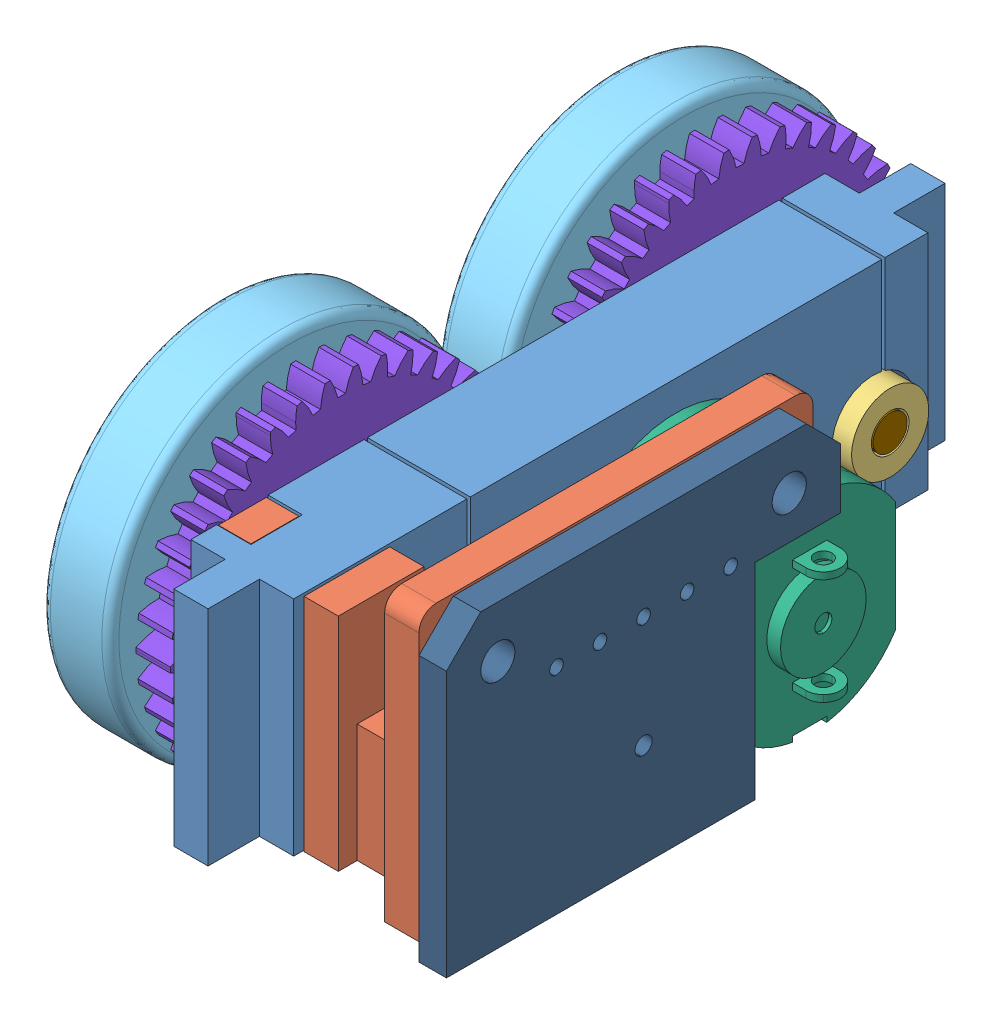
SolidWorks assembly CumBanh1, configuration Default. Lengths in mm.
Overall size (26.61 22.13 47.3).
19 component instances, 12 part files, 39 mates.
Components (placement in the parent):
- Cum Banh 1-1: Cum Banh 1 [Default] at (16.5178 20.2239 29.5226) x (0 0 -1) z (1 0 0) size (43 13 7.5)
- Ga encoder 1-1: Ga encoder 1 [Default] at (28.5178 23.2543 41.2226) x (0 0 -1) z (0 -1 0) size (23 14 16.6)
- Ga nam chamV3-1: Ga nam chamV3 [Default] at (21.0178 20.2239 18.0226) x (1 0 0) z (0 -0.059126 0.998251) size (2.5 4.5 4.5)
- Ga nam chamV3.1-1: Ga nam chamV3.1 [Default] at (20.5178 20.2239 41.0226) x (1 0 0) z (0 -0.620557 0.784161) size (7 7.5 7.5)
- Lop banh xe-1: Lop banh xe [Default] at (6.5178 20.2239 41.0226) size (4 21 21)
- N20 DC MOTOR Truc dai-1: N20 DC MOTOR Truc dai [Default] at (30.3178 20.1445 29.5225) x (0 1 0) z (0 0 1) size (12.48 22.6 10.65)
- Nam cham-1: Nam cham [Default] at (26.5178 20.2239 41.0226) x (0 -0.952578 -0.304296) z (1 0 0) size (4 4 2)
- Part4-1: Part4 [Default] at (12.5178 20.2239 41.0226) x (-1 0 0) z (0 0 -1) (suppressed, hidden)
- Spur gear 0.5M 38T-1: Spur gear 0.5M 38T [Default] at (12.5178 20.2239 41.0226) size (5 19.95 20)
- Truc 2x20-1: Truc 2x20 [Default] at (14.5178 20.2239 41.0226) x (0 0 -1) z (1 0 0) size (2 2 18)
- MT6701 Ver2-1: MT6701 Ver2 [Default] at (32.1278 20.2239 41.0226) x (0 0 -1) z (-1 0 0) size (23 17.5 3.61)
- Part4-2: Part4 [Default] at (12.5178 20.2239 18.0226) x (-1 0 0) z (0 0 -1) (suppressed, hidden)
- Truc 2x20-2: Truc 2x20 [Default] at (14.5178 20.2239 18.0226) x (0 0.989004 -0.147887) z (1 0 0) size (2 2 18)
- Lop banh xe-2: Lop banh xe [Default] at (6.5178 20.2239 18.0226) size (4 21 21)
- Spur gear 0.5M 38T-2: Spur gear 0.5M 38T [Default] at (12.5178 20.2239 18.0226) x (1 0 0) z (0 0.027407 0.999624) size (5 19.95 20)
- Vong bi 2x5x2.5-2: Vong bi 2x5x2.5 [Default] at (18.627 20.2239 41.0226) x (0 0 -1) z (1 0 0) size (5 5 3)
- Vong bi 2x5x2.5-3: Vong bi 2x5x2.5 [Default] at (21.627 20.2239 41.0226) x (0 0 -1) z (1 0 0) size (5 5 3)
- Vong bi 2x5x2.5-4: Vong bi 2x5x2.5 [Default] at (18.627 20.2239 18.0226) x (0 0 -1) z (1 0 0) size (5 5 3)
- Vong bi 2x5x2.5-6: Vong bi 2x5x2.5 [Default] at (21.627 20.2239 18.0226) x (0 0 -1) z (1 0 0) size (5 5 3)
Mates (geometry in assembly coordinates):
- Concentric1: concentric aligned: cylinder of Cum Banh 1-1 through (22.5178 20.2239 41.0226) axis (-1 0 0) radius 2.6; cylinder of Truc 2x20-1 through (23.5178 20.2239 41.0226) axis (-1 0 0) radius 1
- Concentric2: concentric aligned: cylinder of Cum Banh 1-1 through (22.5178 20.2239 41.0226) axis (-1 0 0) radius 2.6; cylinder of Lop banh xe-1 through (6.5178 20.2239 41.0226) axis (-1 0 0) radius 5.5
- Concentric3: concentric anti-aligned: cylinder of Cum Banh 1-1 through (22.5178 20.2239 41.0226) axis (-1 0 0) radius 2.6; cylinder of Part4-1 through (12.5178 20.2239 41.0226) axis (1 0 0) radius 5.1
- Concentric4: concentric anti-aligned: cylinder of Cum Banh 1-1 through (22.5178 20.2239 41.0226) axis (-1 0 0) radius 2.6; cylinder of Spur gear 0.5M 38T-1 through (9.5178 20.2239 41.0226) axis (1 0 0) radius 2.5
- Concentric5: concentric anti-aligned: cylinder of Cum Banh 1-1 through (22.5178 20.2239 41.0226) axis (-1 0 0) radius 2.6; cylinder of Vong bi 2x5x2.5-2 through (18.627 20.2239 41.0226) axis (1 0 0) radius 2.5
- Concentric6: concentric anti-aligned: cylinder of Cum Banh 1-1 through (22.5178 20.2239 41.0226) axis (-1 0 0) radius 2.6; cylinder of Vong bi 2x5x2.5-3 through (21.627 20.2239 41.0226) axis (1 0 0) radius 2.5
- Concentric7: concentric aligned: cylinder of Cum Banh 1-1 through (22.5178 20.2239 41.0226) axis (-1 0 0) radius 2.6; cylinder of Ga nam chamV3.1-1 through (20.5178 20.2239 41.0226) axis (-1 0 0) radius 3.75
- Concentric8: concentric aligned: cylinder of Cum Banh 1-1 through (22.5178 20.2239 41.0226) axis (-1 0 0) radius 2.6; cylinder of Nam cham-1 through (27.5178 20.2239 41.0226) axis (-1 0 0) radius 2
- Concentric9: concentric aligned: cylinder of Cum Banh 1-1 through (22.5178 20.2239 41.0226) axis (-1 0 0) radius 2.6; cylinder of MT6701 Ver2-1 through (33.5178 20.2239 41.0226) axis (-1 0 0) radius 0.5
- Concentric10: concentric aligned: cylinder of Cum Banh 1-1 through (22.5178 20.2239 18.0226) axis (-1 0 0) radius 2.6; cylinder of Ga nam chamV3-1 through (21.0178 20.2239 18.0226) axis (-1 0 0) radius 2.25
- Concentric11: concentric anti-aligned: cylinder of Cum Banh 1-1 through (22.5178 20.2239 18.0226) axis (-1 0 0) radius 2.6; cylinder of Spur gear 0.5M 38T-2 through (9.5178 20.2239 18.0226) axis (1 0 0) radius 2.5
- Concentric12: concentric anti-aligned: cylinder of Cum Banh 1-1 through (22.5178 20.2239 18.0226) axis (-1 0 0) radius 2.6; cylinder of Part4-2 through (12.5178 20.2239 18.0226) axis (1 0 0) radius 5.1
- Concentric13: concentric aligned: cylinder of Cum Banh 1-1 through (22.5178 20.2239 18.0226) axis (-1 0 0) radius 2.6; cylinder of Lop banh xe-2 through (6.5178 20.2239 18.0226) axis (-1 0 0) radius 5.5
- Concentric14: concentric aligned: cylinder of Cum Banh 1-1 through (22.5178 20.2239 18.0226) axis (-1 0 0) radius 2.6; cylinder of Truc 2x20-2 through (23.5178 20.2239 18.0226) axis (-1 0 0) radius 1
- Concentric15: concentric aligned: cylinder of MT6701 Ver2-1 through (35.6278 28.7239 49.5226) axis (-1 0 0) radius 1; cylinder of Ga encoder 1-1 through (30.5178 28.7239 49.5226) axis (-1 0 0) radius 1
- Coincident1: coincident anti-aligned: plane of Part4-1 through (11.5178 20.2239 48.5226) normal (-1 0 0); plane of Lop banh xe-1 through (11.5178 30.7239 41.0226) normal (1 0 0)
- Coincident2: coincident anti-aligned: plane of Part4-1 through (12.5178 20.2239 43.5226) normal (1 0 0); plane of Spur gear 0.5M 38T-1 through (12.5178 20.2239 41.0226) normal (-1 0 0)
- Coincident3: coincident anti-aligned: plane of Spur gear 0.5M 38T-2 through (12.5178 20.2239 18.0226) normal (-1 0 0); plane of Part4-2 through (12.5178 20.2239 20.5226) normal (1 0 0)
- Coincident4: coincident anti-aligned: plane of Lop banh xe-2 through (11.5178 30.7239 18.0226) normal (1 0 0); plane of Part4-2 through (11.5178 20.2239 25.5226) normal (-1 0 0)
- Coincident5: coincident anti-aligned: plane of Vong bi 2x5x2.5-3 through (17.5178 22.7239 41.0226) normal (-1 0 0); plane of Vong bi 2x5x2.5-2 through (17.5178 22.2239 41.0226) normal (1 0 0)
- Coincident6: coincident anti-aligned: plane of Vong bi 2x5x2.5-4 through (17.5178 22.2239 18.0226) normal (1 0 0); plane of Vong bi 2x5x2.5-6 through (17.5178 22.7239 18.0226) normal (-1 0 0)
- Coincident7: coincident aligned: plane of Truc 2x20-1 through (5.5178 20.2239 41.0226) normal (-1 0 0); plane of Part4-1 through (5.5178 20.2239 42.1226) normal (-1 0 0)
- Coincident8: coincident aligned: plane of Truc 2x20-1 through (5.5178 20.2239 41.0226) normal (-1 0 0); plane of Truc 2x20-2 through (5.5178 20.2239 18.0226) normal (-1 0 0)
- Coincident9: coincident aligned: plane of Truc 2x20-1 through (5.5178 20.2239 41.0226) normal (-1 0 0); plane of Part4-2 through (5.5178 20.2239 19.1226) normal (-1 0 0)
- Coincident10: coincident anti-aligned: plane of Cum Banh 1-1 through (20.5178 20.2239 41.0226) normal (-1 0 0); plane of Vong bi 2x5x2.5-3 through (20.5178 22.2239 41.0226) normal (1 0 0)
- Coincident11: coincident anti-aligned: plane of Cum Banh 1-1 through (20.5178 20.2239 18.0226) normal (-1 0 0); plane of Vong bi 2x5x2.5-6 through (20.5178 22.2239 18.0226) normal (1 0 0)
- Concentric16: concentric anti-aligned: cylinder of N20 DC MOTOR Truc dai-1 through (15.4178 20.2239 29.5226) axis (1 0 0) radius 5.9205; cylinder of Cum Banh 1-1 through (22.5178 20.2239 29.5226) axis (-1 0 0) radius 6.25
- Parallel1: parallel aligned: plane of N20 DC MOTOR Truc dai-1 through (15.4178 16.8945 24.5225) normal (0 0 -1); plane of Cum Banh 1-1 through (22.5178 20.2239 34.6226) normal (0 0 -1)
- Concentric17: concentric aligned: cylinder of Vong bi 2x5x2.5-4 through (18.627 20.2239 18.0226) axis (1 0 0) radius 2.5; cylinder of Vong bi 2x5x2.5-6 through (21.627 20.2239 18.0226) axis (1 0 0) radius 2.5
- Concentric18: concentric anti-aligned: cylinder of Vong bi 2x5x2.5-4 through (18.627 20.2239 18.0226) axis (1 0 0) radius 2.5; cylinder of Cum Banh 1-1 through (22.5178 20.2239 18.0226) axis (-1 0 0) radius 2.6
- Coincident13: coincident anti-aligned: plane of Ga nam chamV3.1-1 through (25.5178 21.8706 42.3258) normal (1 0 0); plane of Nam cham-1 through (25.5178 20.2239 41.0226) normal (-1 0 0)
- Coincident14: coincident anti-aligned: plane of Truc 2x20-1 through (23.5178 20.2239 41.0226) normal (1 0 0); plane of Ga nam chamV3.1-1 through (23.5178 20.2239 41.0226) normal (-1 0 0)
- Coincident15: coincident anti-aligned: plane of Spur gear 0.5M 38T-2 through (14.5178 20.2239 18.0226) normal (1 0 0); plane of N20 DC MOTOR Truc dai-1 through (14.5178 20.1176 29.5147) normal (-1 0 0)
- Coincident18: coincident anti-aligned: plane of Ga encoder 1-1 through (30.5178 23.2543 31.6226) normal (1 0 0); plane of MT6701 Ver2-1 through (30.5178 20.2239 41.0226) normal (-1 0 0)
- Concentric19: concentric aligned: cylinder of Ga encoder 1-1 through (30.5178 28.7239 32.5226) axis (-1 0 0) radius 1; cylinder of MT6701 Ver2-1 through (35.6278 28.7239 32.5226) axis (-1 0 0) radius 1
- Distance1: distance = 1 mm anti-aligned: plane of Nam cham-1 through (27.5178 20.2239 41.0226) normal (1 0 0); plane of MT6701 Ver2-1 through (28.5178 20.2239 41.0226) normal (-1 0 0)
- Parallel5: parallel aligned: plane of Cum Banh 1-1 through (22.5178 15.2239 29.5226) normal (0 -1 0); plane of Ga encoder 1-1 through (30.5178 15.2543 47.8226) normal (0 -1 0)
- Coincident23: coincident anti-aligned: plane of Spur gear 0.5M 38T-2 through (14.5178 20.2239 18.0226) normal (1 0 0); plane of Vong bi 2x5x2.5-4 through (14.5178 22.7239 18.0226) normal (-1 0 0)
- Coincident24: coincident aligned: plane of Ga nam chamV3-1 through (23.5178 21.322 18.0877) normal (1 0 0); plane of Truc 2x20-2 through (23.5178 20.2239 18.0226) normal (1 0 0)
